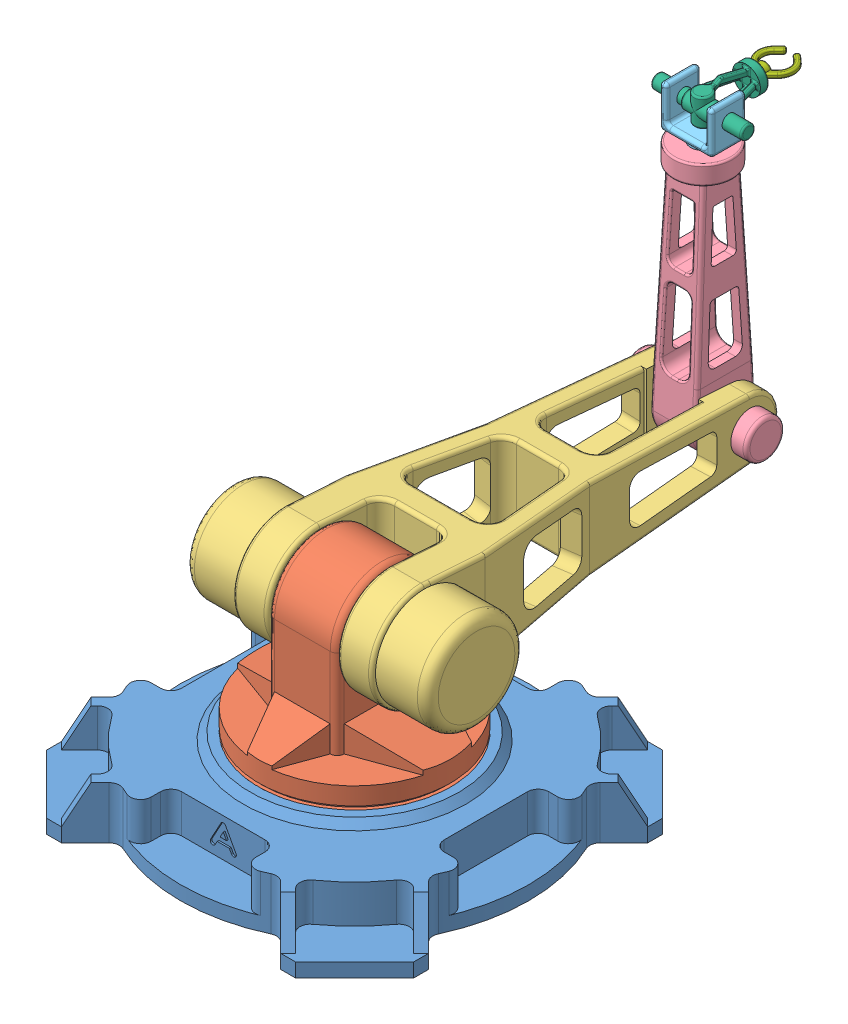
SolidWorks assembly Agnes, configuration Default. Lengths in mm.
Overall size (1053.59 1277.76 1785.25).
7 component instances, 7 part files, 15 mates.
Components (placement in the parent):
- lk_0-1: lk_0 [Default] x (1 0 0) z (0 1 0) size (1053.59 1053.59 170)
- lk_1-1: lk_1 [Default] at (0 110 0) x (1 0 0) z (0 1 0) size (550 550 525)
- lk_2-1: lk_2 [Default] at (0 485 0) x (0 0 -1) z (1 0 0) size (1237.5 301.13 700)
- lk_3-1: lk_3 [Default] at (0 485 -1000) x (0 1 0) z (1 0 0) size (742.5 176.13 360)
- lk_4-2: lk_4 [Default] at (0 1125 -1000) x (1 0 0) z (0 1 0) size (150 100 150)
- lk_5-2: lk_5 [Default] at (0 1225 -1000) x (0 0.022772 -0.999741) z (1 0 0) size (175 98.72 260)
- lk_6-2: lk_6 [Default] at (0 1228.188 -1139.9637) x (0.999042 0.043759 0.000997) z (0 0.022772 -0.999741) size (107.32 40 118.01)
Mates (geometry in assembly coordinates):
- Coincident1: coincident anti-aligned: plane of lk_0-1 through (0 110 0) normal (0 1 0); plane of lk_1-1 through (0 110 0) normal (0 -1 0)
- Concentric2: concentric aligned: cylinder of lk_0-1 through (0 170 0) axis (0 -1 0) radius 275; cylinder of lk_1-1 through (0 180 0) axis (0 -1 0) radius 275
- Coincident2: coincident anti-aligned: plane of lk_1-1 through (100 485 0) normal (1 0 0); plane of lk_2-1 through (100 335 0) normal (-1 0 0)
- Concentric3: concentric aligned: cylinder of lk_1-1 through (100 485 0) axis (-1 0 0) radius 100; cylinder of lk_2-1 through (200 485 0) axis (-1 0 0) radius 100
- Concentric4: concentric anti-aligned: cylinder of lk_2-1 through (-350 485 -1000) axis (1 0 0) radius 55; cylinder of lk_3-1 through (180 485 -1000) axis (-1 0 0) radius 55
- Coincident4: coincident anti-aligned: plane of lk_3-1 through (0 1125 -1000) normal (0 1 0); plane of lk_4-2 through (0 1125 -1000) normal (0 -1 0)
- Concentric5: concentric anti-aligned: cylinder of lk_3-1 through (0 1125 -1000) axis (0 1 0) radius 35; cylinder of lk_4-2 through (0 1155 -1000) axis (0 -1 0) radius 35
- Concentric6: concentric aligned: cylinder of lk_4-2 through (75 1225 -1000) axis (-1 0 0) radius 20; cylinder of lk_5-2 through (90 1225 -1000) axis (-1 0 0) radius 20
- Distance2: distance = 10 mm anti-aligned: plane of lk_3-1 through (65 485 -1000) normal (1 0 0); plane of lk_2-1 through (75 335 0) normal (-1 0 0)
- Parallel3: parallel aligned: plane of lk_2-1 through (0 485 0) normal (0 1 0)
- Coincident11: coincident aligned: plane of lk_4-2 through (0 1125 -1000) normal (1 0 0); plane of lk_5-2 through (0 1225 -1000) normal (1 0 0)
- Concentric7: concentric anti-aligned: cylinder of lk_5-2 through (0 1228.188 -1139.9637) axis (0 0.022772 -0.999741) radius 20; cylinder of lk_6-2 through (0 1229.0989 -1179.9533) axis (0 -0.022772 0.999741) radius 20
- Coincident12: coincident anti-aligned: plane of lk_5-2 through (0 1228.188 -1139.9637) normal (0 0.022772 -0.999741); plane of lk_6-2 through (0 1228.188 -1139.9637) normal (0 -0.022772 0.999741)
- Parallel4: parallel aligned: plane of lk_3-1 through (0 485 -1000) normal (0 0 1)
- Parallel5: parallel anti-aligned: plane of lk_4-2 through (0 1125 -1000) normal (0 0 -1)
